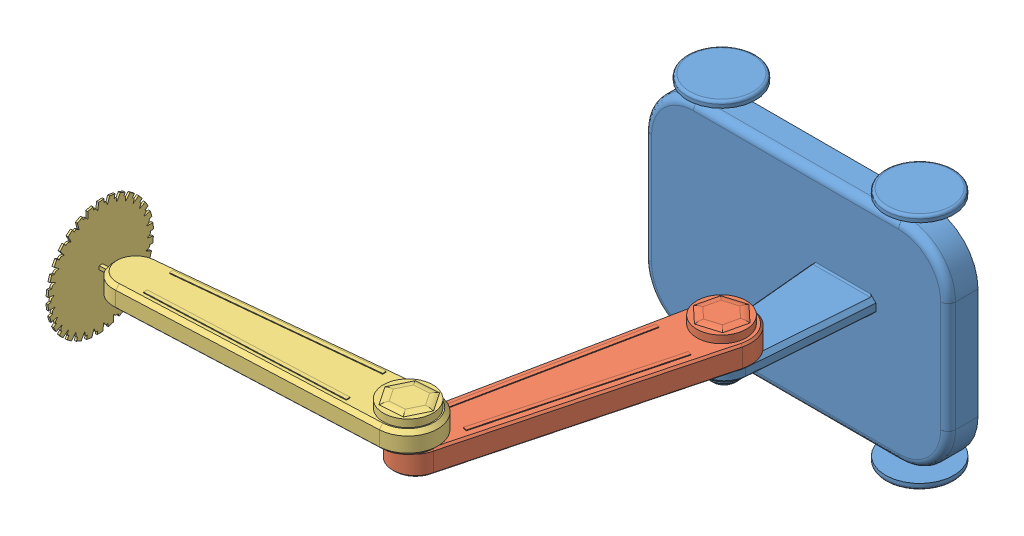
SolidWorks assembly assemble1, configuration Default. Lengths in mm.
Overall size (307.19 159.3 340.91).
3 component instances, 3 part files, 4 mates.
Components (placement in the parent):
- base_1-1: base_1 [Default] at (108.7948 82.0594 132.506) size (203.2 159.3 134.66)
- arm_1-1: arm_1 [Default] at (91.0329 94.5594 307.599) x (-0.226785 0 0.973945) z (-0.973945 0 -0.226785) size (205.25 31.02 40)
- arm_2-1: arm_2 [Default] at (-9.178 109.5594 407.8768) x (-0.997425 0 0.071722) z (-0.071722 0 -0.997425) size (213.12 76.2 76.14)
Mates (geometry in assembly coordinates):
- Coincident1: coincident anti-aligned: plane of base_1-1 through (108.7948 87.0594 232.506) normal (0 1 0); plane of arm_1-1 through (107.5344 87.0594 233.6801) normal (0 -1 0)
- Concentric1: concentric aligned: cylinder of base_1-1 through (108.6686 77.0594 231.8608) axis (0 1 0) radius 5; cylinder of arm_1-1 through (108.6686 77.0594 231.8608) axis (0 1 0) radius 5
- Coincident2: coincident anti-aligned: plane of arm_1-1 through (107.5344 102.0594 233.6801) normal (0 1 0); plane of arm_2-1 through (66.3125 102.0594 401.7547) normal (0 -1 0)
- Concentric2: concentric aligned: cylinder of arm_1-1 through (68.3861 92.0594 402.2994) axis (0 1 0) radius 5; cylinder of arm_2-1 through (68.3861 92.0594 402.2994) axis (0 1 0) radius 5
